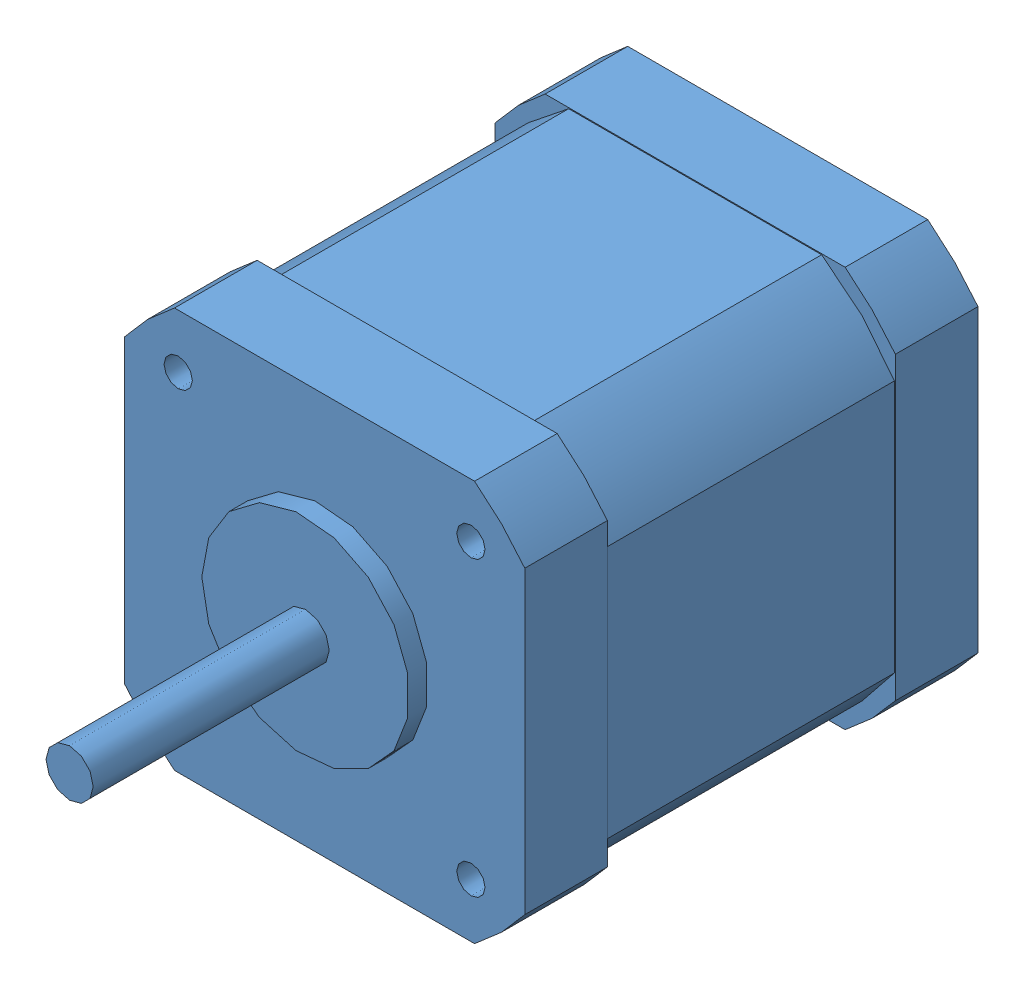
SolidWorks assembly Assem1, configuration Default. Lengths in mm.
Overall size (42.42 48.42 75).
2 component instances, 2 part files, 3 mates.
Components (placement in the parent):
- MT-1704HSM168RE-1: MT-1704HSM168RE [Default] at (17.9612 39.1749 62.8395) size (42.42 47.17 75)
- User Library-b6b-ph-ks-1: User Library-b6b-ph-ks [Default] at (17.9612 17.9659 21.5895) x (-1 0 0) z (0 0 1) size (13.9 9 4.5)
Mates (geometry in assembly coordinates):
- Coincident1: coincident: plane of MT-1704HSM168RE-1 through (-3.2478 17.9659 14.8395) normal (0 -1 0); plane of User Library-b6b-ph-ks-1 through (24.9112 17.9659 23.8395) normal (0 1 0)
- Coincident2: coincident: plane of MT-1704HSM168RE-1 through (9.9612 13.2159 19.3395) normal (0 0 1); plane of User Library-b6b-ph-ks-1 through (24.9112 11.9659 19.3395) normal (0 0 -1)
- Width1: width anti-aligned: plane of MT-1704HSM168RE-1 through (25.9612 13.2159 14.8395) normal (1 0 0); plane of User Library-b6b-ph-ks-1 through (9.9612 13.2159 14.8395) normal (-1 0 0); plane of MT-1704HSM168RE-1 through (11.0112 11.9659 19.3395) normal (-1 0 0); plane of User Library-b6b-ph-ks-1 through (24.9112 11.9659 19.3395) normal (1 0 0)
